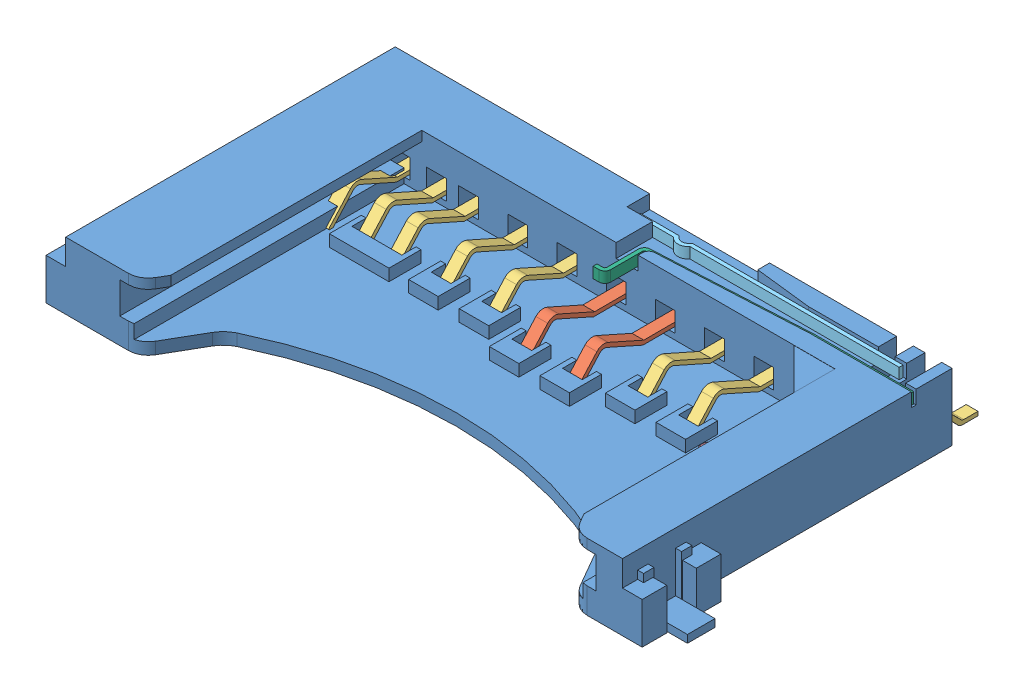
SolidWorks assembly raspberry_pi__SD_reader_assembly, configuration Valor predeterminado. Lengths in mm.
Overall size (32.3 4.2 18.72).
16 component instances, 6 part files, 17 mates.
Components (placement in the parent):
- raspberry_pi__SD_reader_body-1: raspberry_pi__SD_reader_body [Default] at (-67.8965 -2.1406 21.2643) size (32.3 4.2 16.75)
- raspberry_pi__SD_reader_pin1-1: raspberry_pi__SD_reader_pin1 [Valor predeterminado] at (-66.0305 -2.1406 -4.4304) x (0 0 -1) z (1 0 0) size (9.85 2.04 0.6)
- raspberry_pi__SD_reader_pin1-2: raspberry_pi__SD_reader_pin1 [Valor predeterminado] at (-68.5305 -2.1406 -4.4304) x (0 0 -1) z (1 0 0) size (9.85 2.04 0.6)
- raspberry_pi__SD_reader_pin2-1: raspberry_pi__SD_reader_pin2 [Valor predeterminado] at (-76.0205 -2.1385 -5.3387) x (0 0 -1) z (1 0 0) size (8.94 2.04 0.6)
- raspberry_pi__SD_reader_pin2-2: raspberry_pi__SD_reader_pin2 [Valor predeterminado] at (-73.5205 -2.1385 -5.3387) x (0 0 -1) z (1 0 0) size (8.94 2.04 0.6)
- raspberry_pi__SD_reader_pin2-3: raspberry_pi__SD_reader_pin2 [Valor predeterminado] at (-71.0205 -2.1385 -5.3387) x (0 0 -1) z (1 0 0) size (8.94 2.04 0.6)
- raspberry_pi__SD_reader_pin2-4: raspberry_pi__SD_reader_pin2 [Valor predeterminado] at (-63.5205 -2.1385 -5.3387) x (0 0 -1) z (1 0 0) size (8.94 2.04 0.6)
- raspberry_pi__SD_reader_pin2-5: raspberry_pi__SD_reader_pin2 [Valor predeterminado] at (-61.0205 -2.1385 -5.3387) x (0 0 -1) z (1 0 0) size (8.94 2.04 0.6)
- raspberry_pi__SD_reader_pin2-6: raspberry_pi__SD_reader_pin2 [Valor predeterminado] at (-77.6455 -2.1385 -5.3387) x (0 0 -1) z (1 0 0) size (8.94 2.04 0.6)
- raspberry_pi__SD_reader_pin2-7: raspberry_pi__SD_reader_pin2 [Valor predeterminado] at (-79.4655 -2.1385 -5.3387) x (0 0 -1) z (1 0 0) size (8.94 2.04 0.6)
- raspberry_pi__SD_reader_pin2-8: raspberry_pi__SD_reader_pin2 [Valor predeterminado] at (-81.1155 -2.1385 -5.3387) x (0 0 -1) z (1 0 0) size (8.94 2.04 0.6)
- raspberry_pi__SD_reader_pin2-9: raspberry_pi__SD_reader_pin2 [Valor predeterminado] at (-56.8355 -2.1385 -5.3387) x (0 0 -1) z (1 0 0) size (8.94 2.04 0.6)
- raspberry_pi__SD_reader_pin2-10: raspberry_pi__SD_reader_pin2 [Valor predeterminado] at (-55.3955 -2.1385 -5.3387) x (0 0 -1) z (1 0 0) size (8.94 2.04 0.6)
- raspberry_pi__SD_reader_pin3-1: raspberry_pi__SD_reader_pin3 [Valor predeterminado] at (-58.5401 -2.1448 -2.5387) x (0 0 -1) z (1 0 0) size (11.74 2.04 0.6)
- raspberry_pi__SD_reader_pin4-1: raspberry_pi__SD_reader_pin4 [Valor predeterminado] at (-62.6615 0.5594 -20.2143) x (1 0 0) z (0 1 0) size (13.35 0.4 0.55)
- raspberry_pi__SD_reader_pin5-1: raspberry_pi__SD_reader_pin5 [Valor predeterminado] at (-67.8965 0.5594 -4.5143) x (1 0 0) z (0 1 0) size (13.67 2.63 0.55)
Mates (geometry in assembly coordinates):
- Paralelo1: parallel aligned: plane of raspberry_pi__SD_reader_body-1 through (-54.4465 1.2594 -4.5143) normal (1 0 0); plane of raspberry_pi__SD_reader_pin1-1 through (-65.7305 -1.8406 -22.4304) normal (1 0 0)
- Coincidente2: coincident aligned: plane of raspberry_pi__SD_reader_body-1 through (-56.2439 -2.1406 -5.5143) normal (0 -1 0); plane of raspberry_pi__SD_reader_pin1-1 through (-65.7305 -2.1406 -23.2304) normal (0 -1 0)
- Paralelo2: parallel aligned: plane of raspberry_pi__SD_reader_body-1 through (-82.7465 1.2594 -4.5143) normal (-1 0 0); plane of raspberry_pi__SD_reader_pin2-1 through (-76.3205 -1.8406 -22.4304) normal (-1 0 0)
- Coincidente4: coincident aligned: plane of raspberry_pi__SD_reader_pin1-2 through (-68.2305 -1.9406 -22.5094) normal (0 1 0); plane of raspberry_pi__SD_reader_pin2-1 through (-75.7205 -1.9406 -22.5094) normal (0 1 0)
- Coincidente5: coincident aligned: plane of raspberry_pi__SD_reader_pin1-2 through (-68.2305 -1.9406 -23.2304) normal (0 0 -1); plane of raspberry_pi__SD_reader_pin2-1 through (-75.7205 -1.9406 -23.2304) normal (0 0 -1)
- Paralelo3: parallel aligned: plane of raspberry_pi__SD_reader_pin2-4 through (-63.2205 -1.8406 -22.4304) normal (1 0 0); plane of raspberry_pi__SD_reader_pin3-1 through (-58.2401 -1.8406 -22.4304) normal (1 0 0)
- Coincidente7: coincident aligned: plane of raspberry_pi__SD_reader_pin2-6 through (-77.3455 -1.9406 -23.2304) normal (0 0 -1); plane of raspberry_pi__SD_reader_pin3-1 through (-58.2401 -1.9406 -23.2304) normal (0 0 -1)
- Coincidente9: coincident aligned: plane of raspberry_pi__SD_reader_pin2-1 through (-75.7205 -1.9406 -22.5094) normal (0 1 0); plane of raspberry_pi__SD_reader_pin3-1 through (-58.2401 -1.9406 -22.5094) normal (0 1 0)
- Coincidente10: coincident aligned: plane of raspberry_pi__SD_reader_pin1-2 through (-68.2305 -1.9406 -22.5094) normal (0 1 0); plane of raspberry_pi__SD_reader_pin2-1 through (-75.7205 -1.9406 -22.5094) normal (0 1 0)
- Coincidente11: coincident aligned: plane of raspberry_pi__SD_reader_pin1-2 through (-68.2305 -1.9406 -23.2304) normal (0 0 -1); plane of raspberry_pi__SD_reader_pin2-1 through (-75.7205 -1.9406 -23.2304) normal (0 0 -1)
- Paralelo4: parallel aligned: plane of raspberry_pi__SD_reader_body-1 through (-82.7465 1.2594 -21.2643) normal (0 0 -1); plane of raspberry_pi__SD_reader_pin4-1 through (-66.6621 1.1094 -20.3143) normal (0 0 -1)
- Coincidente13: coincident: plane of raspberry_pi__SD_reader_body-1 through (-69.8165 0.5594 -20.1143) normal (0 0 -1); moEndPointRef_w of raspberry_pi__SD_reader_pin4-1
- Distância1: distance = 0.15 mm aligned: plane of raspberry_pi__SD_reader_body-1 through (-56.2439 1.2594 -5.5143) normal (0 1 0); plane of raspberry_pi__SD_reader_pin4-1 through (-66.6621 1.1094 -20.2143) normal (0 1 0)
- Distância2: distance = 0.82 mm anti-aligned: plane of raspberry_pi__SD_reader_pin4-1 through (-69.3365 1.1094 -20.1143) normal (-1 0 0); plane of raspberry_pi__SD_reader_body-1 through (-68.5165 0.5594 -20.1143) normal (1 0 0)
- Distância3: distance = 0.1 mm aligned: plane of raspberry_pi__SD_reader_pin5-1 through (-54.5465 1.1094 -19.4143) normal (1 0 0); plane of raspberry_pi__SD_reader_body-1 through (-54.4465 1.2594 -4.5143) normal (1 0 0)
- Distância4: distance = 0.02 mm anti-aligned: plane of raspberry_pi__SD_reader_body-1 through (-54.9719 0.5594 -19.4343) normal (0 0 1); plane of raspberry_pi__SD_reader_pin5-1 through (-59.5421 1.1094 -19.4143) normal (0 0 -1)
- Distância5: distance = 0.15 mm aligned: plane of raspberry_pi__SD_reader_body-1 through (-56.2439 1.2594 -5.5143) normal (0 1 0); plane of raspberry_pi__SD_reader_pin5-1 through (-67.9156 1.1094 -17.0853) normal (0 1 0)
